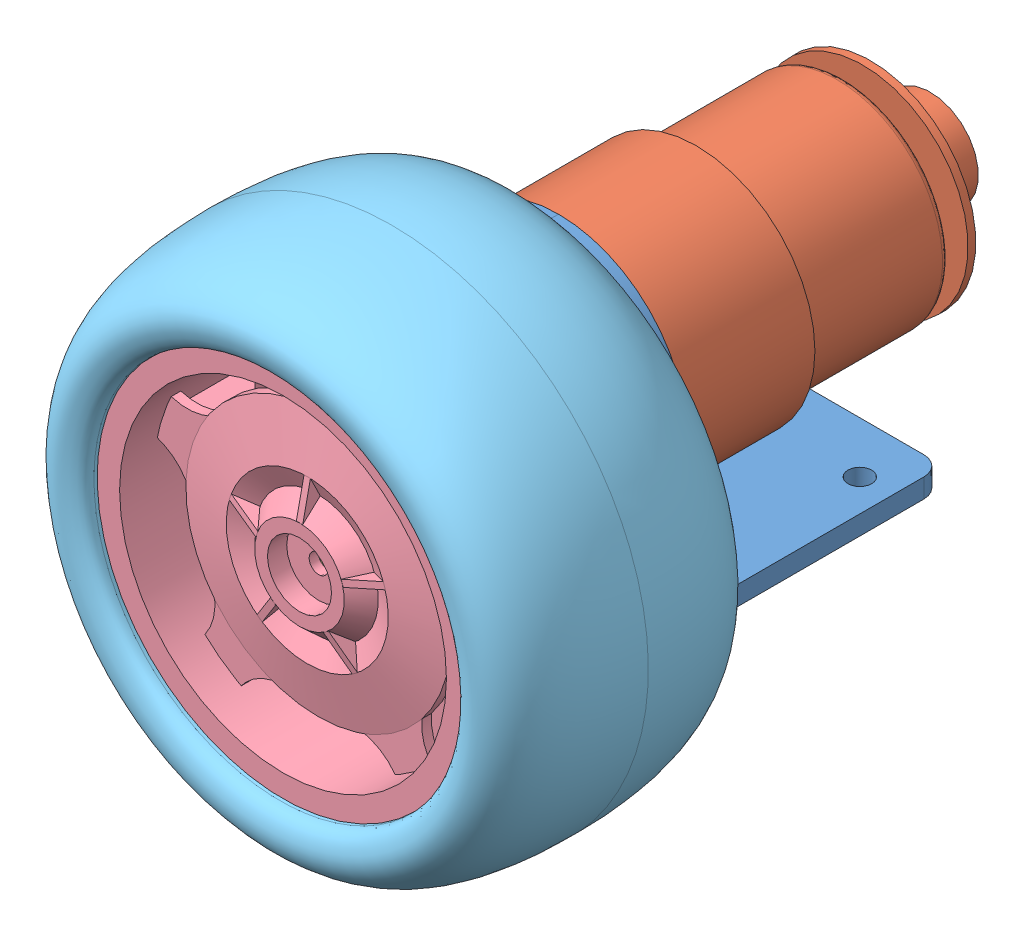
SolidWorks assembly Motor_assembly, configuration Défaut. Lengths in mm.
Overall size (104.6 104.6 104.35).
5 component instances, 5 part files, 10 mates.
Components (placement in the parent):
- Support-1: Support [Défaut] at (-3.961 -24.6388 68.5) size (40 47 43)
- Moteur-1: Moteur [Défaut] at (-3.961 2.3612 21) x (-1 0 0) z (0 0 1) size (37 37 79)
- Attache_moteur-1: Attache_moteur [Défaut] at (-3.961 -6.1388 71.4953) size (13.86 12 30)
- Roue-1: Roue [Défaut] at (-3.961 -6.1388 101.4953) x (-1 0 0) z (0 0 -1) size (58 58 35)
- Pneu-1: Pneu [Défaut] at (-3.961 -6.1388 91.4953) x (0.923728 0.383049 0) z (0 0 -1) size (80.04 80.04 40.7)
Mates (geometry in assembly coordinates):
- Coïncidente1: coincident anti-aligned: plane of Support-1 through (16.039 22.3612 65.5) normal (0 0 -1); plane of Moteur-1 through (-3.961 -16.1388 65.5) normal (0 0 1)
- Coïncidente2: coincident anti-aligned: plane of Moteur-1 through (-3.961 -12.1388 71.4953) normal (0 0 1); plane of Attache_moteur-1 through (-99.3154 -100.7374 71.4953) normal (0 0 -1)
- Coïncidente3: coincident anti-aligned: plane of Attache_moteur-1 through (-95.8513 -94.7374 101.4953) normal (0 1 0); plane of Roue-1 through (-102.7795 -94.7374 101.4953) normal (0 -1 0)
- Coïncidente4: coincident anti-aligned: plane of Attache_moteur-1 through (-92.3872 -100.7374 101.4953) normal (0.866025 0.5 0); plane of Roue-1 through (-95.8513 -94.7374 101.4953) normal (-0.866025 -0.5 0)
- Coïncidente5: coincident anti-aligned: plane of Attache_moteur-1 through (-99.3154 -100.7374 101.4953) normal (0 0 1); plane of Roue-1 through (-99.3154 -100.7374 101.4953) normal (0 0 -1)
- Coaxiale6: concentric anti-aligned: cylinder of Roue-1 through (-99.3154 -100.7374 101.4953) axis (0 0 1) radius 29; cylinder of Pneu-1 through (-99.3154 -100.7374 91.4953) axis (0 0 -1) radius 29
- Distance1: distance = 10 mm aligned: plane of Pneu-1 through (-3.961 -6.1388 91.4953) normal (0 0 -1); plane of Roue-1 through (-3.961 -6.1388 101.4953) normal (0 0 -1)
- Coaxiale9: concentric aligned: cylinder of Support-1 through (11.539 2.3612 68.5) axis (0 0 1) radius 1.6; cylinder of Moteur-1 through (11.539 2.3612 65.5) axis (0 0 1) radius 1.7
- Coaxiale10: concentric aligned: cylinder of Support-1 through (-19.461 2.3612 68.5) axis (0 0 1) radius 1.6; cylinder of Moteur-1 through (-19.461 2.3612 65.5) axis (0 0 1) radius 1.7
- Coaxiale11: concentric aligned: cylinder of Moteur-1 through (-3.961 -6.1388 71.4953) axis (0 0 -1) radius 3; cylinder of Attache_moteur-1 through (-3.961 -6.1388 101.4963) axis (0 0 -1) radius 3
